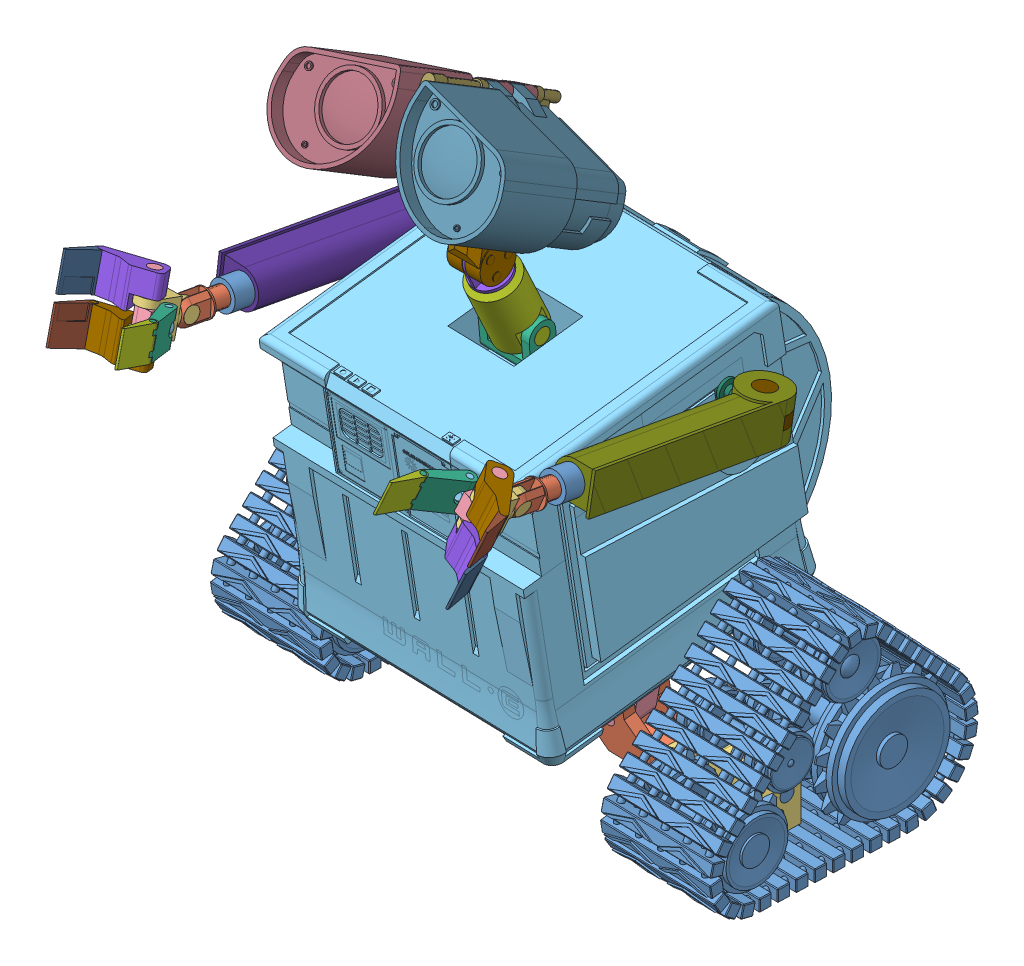
SolidWorks assembly Wall-E 1, configuration Default. Lengths in mm.
Overall size (690.22 894.54 668.06).
46 component instances, 29 part files, 72 mates.
Components (placement in the parent):
- Leg2-1: Leg2 [Default] at (217.59 79.9141 -697.9774) x (0.99964 0 0.026846) z (-0.026526 -0.154085 0.987701) size (150 276.28 351.13)
- Leg2-2: Leg2 [Default] at (-312.2225 80.7609 -712.0739) x (0.99964 0 0.026846) z (-0.026526 -0.154085 0.987701) size (150 276.28 351.13)
- Leg4-1: Leg4 [Default] at (37.1535 79.1519 -684.1405) x (0.99964 0 0.026846) z (-0.026526 -0.154085 0.987701) size (110 70 60)
- Leg4-2: Leg4 [Default] at (-132.7888 79.9987 -688.5724) x (-0.99964 0 -0.026846) z (0.026526 0.154085 -0.987701) size (110 70 60)
- Leg5-1: Leg5 [Default] at (-132.6985 80.2592 -691.9322) x (-0.99964 0 -0.026846) z (0.026846 0 -0.99964) size (135 55 55.64)
- Leg5-2: Leg5 [Default] at (37.2437 79.4124 -687.5004) x (0.99964 0 0.026846) z (-0.026846 0 0.99964) size (135 55 55.64)
- Leg1-1: Leg1 [Default] at (-132.7888 79.9987 -688.5724) x (-0.333574 0.932781 0.136559) z (-0.026526 -0.154085 0.987701) size (150 40 60)
- Leg1-2: Leg1 [Default] at (70.4316 182.6045 -667.1078) x (-0.302528 -0.940479 -0.154843) z (-0.026526 -0.154085 0.987701) size (150 40 60)
- Body2-1: Body2 [Default] at (-49.4424 162.8434 -673.41) x (0.99964 0 0.026846) z (-0.026526 -0.154085 0.987701) size (356.05 350.01 438.03)
- Face 1-1: Face 1 [Default] at (-50.7537 476.0577 -624.5826) x (0.99964 0 0.026846) z (-0.026732 -0.092214 0.99538) size (100 57 34)
- Face2-1: Face2 [Default] at (-50.681 490.0498 -627.2924) x (0.99964 0 0.026846) z (-0.024388 -0.418008 0.908116) size (70 90 60)
- Face3-1: Face3 [Default] at (-51.7528 576.8213 -587.38) x (0.999934 0.011214 0.002475) z (0.002437 -0.417857 0.908509) size (48 63.5 48)
- Face4-1: Face4 [Default] at (-52.0276 599.063 -577.1495) x (0.999934 0.011214 0.002475) z (-0.000596 -0.164604 0.98636) size (46 104.21 107.04)
- Face5-1: Face5 [Default] at (-52.7079 657.9316 -569.0132) x (0.999934 0.011214 0.002475) z (-0.000596 -0.164604 0.98636) size (26 40 80)
- Face6-1: Face6 [Default] at (-53.0415 702.5989 -636.5827) x (0.999934 0.011214 0.002475) z (-0.007905 0.515762 0.856695) size (26 40 16)
- Face7-1: Face7 [Default] at (-54.1993 778.8879 -593.2256) x (0.999773 0.021032 -0.003437) z (-0.007905 0.515762 0.856695) size (16 32 195)
- Eye2-1: Eye2 [Default] at (-69.0806 748.885 -657.0094) x (0.964773 0.229228 -0.129102) z (-0.007905 0.515762 0.856695) size (300 112 205)
- Eye1-1: Eye1 [Default] at (-38.4971 749.5099 -657.1034) x (0.974106 -0.189615 0.123143) z (-0.007905 0.515762 0.856695) size (171 112 205)
- Hand1-1: Hand1 [Default] at (-207.8303 456.7753 -735.5854) x (-0.99964 0 -0.026846) z (0.026526 0.154085 -0.987701) size (28 26 26)
- Hand1-2: Hand1 [Default] at (112.0543 456.7753 -726.9947) x (0.99964 0 0.026846) z (-0.026526 -0.154085 0.987701) size (28 26 26)
- Hand3-1: Hand3 [Default] at (170.0334 456.7753 -725.4376) x (0.999906 -0.002222 0.013542) z (-0.012991 0.164692 0.986259) size (60 52 284)
- Hand3(1)-1: Hand3(1) [Default] at (-425.4358 455.9213 -748.0377) x (0.997665 0.005338 0.068095) z (-0.068217 0.1281 0.989412) size (220 52 284)
- Hand2-1: Hand2 [Default] at (-229.8224 456.7753 -736.176) x (-0.99964 0 -0.026846) z (0.026625 -0.128211 -0.991389) size (66 52 60)
- Hand2-2: Hand2 [Default] at (134.0464 456.7753 -726.404) x (0.99964 0 0.026846) z (-0.026479 0.164707 0.985987) size (66 52 60)
- Hand4-1: Hand4 [Default] at (-268.1118 464.8563 -674.6733) x (0.936168 0.351034 0.019098) z (-0.068217 0.1281 0.989412) size (38 38 212)
- Hand4-2: Hand4 [Default] at (167.2152 467.1554 -663.3303) x (0.999913 -0.000092 0.013187) z (-0.012991 0.164692 0.986259) size (38 38 212)
- Hand5-1: Hand5 [Default] at (-271.8637 471.9018 -620.2556) x (-0.994724 -0.084902 -0.057591) z (-0.068217 0.1281 0.989412) size (34 34 222)
- Hand5-2: Hand5 [Default] at (166.5006 476.2135 -609.086) x (-0.952116 0.299277 -0.062517) z (-0.012991 0.164692 0.986259) size (34 34 222)
- Hand6-1: Hand6 [Default] at (-285.6251 498.3152 -416.4198) x (0.994724 0.084902 0.057591) z (0.080154 -0.292778 -0.952815) size (30 45 77)
- Hand6-2: Hand6 [Default] at (163.5456 510.2277 -405.9349) x (-0.952116 0.299277 -0.062517) z (-0.007303 -0.226682 -0.973942) size (30 45 77)
- Hand7-1: Hand7 [Default] at (-289.4725 512.3686 -370.6847) x (-0.064035 0.952404 -0.298038) z (0.080154 -0.292778 -0.952815) size (100 30 24)
- Hand7-2: Hand7 [Default] at (163.8961 521.1084 -359.1857) x (-0.305649 -0.926849 0.218013) z (-0.007303 -0.226682 -0.973942) size (100 30 24)
- Hand8-1: Hand8 [Default] at (-276.5411 513.4723 -369.936) x (-0.080154 0.292778 0.952815) z (-0.064035 0.952404 -0.298038) size (14 21 42)
- Hand8-2: Hand8 [Default] at (151.5186 524.999 -359.9984) x (-0.007303 -0.226682 -0.973942) z (0.305649 0.926849 -0.218013) size (14 21 42)
- Hand9-1: Hand9 [Default] at (-262.3112 514.6868 -369.1122) x (-0.064035 0.952404 -0.298038) z (-0.430732 -0.295777 -0.852635) size (42 16 63)
- Hand9-2: Hand9 [Default] at (137.8982 529.2803 -360.8928) x (-0.305649 -0.926849 0.218013) z (0.359383 -0.324335 -0.875015) size (42 16 63)
- Hand10-1: Hand10 [Default] at (-240.7746 529.4757 -326.4804) x (-0.064035 0.952404 -0.298038) z (-0.033354 -0.300527 -0.95319) size (42 10 48.5)
- Hand10-2: Hand10 [Default] at (119.9291 545.4971 -317.142) x (-0.305649 -0.926849 0.218013) z (0.031108 -0.238569 -0.970627) size (42 10 48.5)
- Finger1-1: Finger1 [Default] at (157.019 500.2543 -354.2804) x (-0.305649 -0.926849 0.218013) z (0.648657 -0.035078 0.760272) size (45.5 28 75)
- Finger1-2: Finger1 [Default] at (-290.9133 533.7976 -377.3906) x (-0.064035 0.952404 -0.298038) z (-0.924558 0.055793 0.376935) size (45.5 28 75)
- Finger2-1: Finger2 [Default] at (-291.8738 548.0837 -381.8611) x (-0.064035 0.952404 -0.298038) z (-0.924558 0.055793 0.376935) size (115 28 75)
- Finger2-2: Finger2 [Default] at (152.4342 486.3516 -351.0102) x (-0.305649 -0.926849 0.218013) z (0.648657 -0.035078 0.760272) size (115 28 75)
- Finger3-1: Finger3 [Default] at (-346.0692 534.2248 -364.175) x (-0.064035 0.952404 -0.298038) z (-0.345331 0.259053 0.902019) size (45.5 10 46.5)
- Finger3-2: Finger3 [Default] at (199.6168 494.9258 -317.2125) x (-0.305649 -0.926849 0.218013) z (0.360206 0.099395 0.927563) size (45.5 10 46.5)
- Finger4-1: Finger4 [Default] at (-339.3455 434.2224 -332.881) x (-0.064035 0.952404 -0.298038) z (-0.345331 0.259053 0.902019) size (96 10 46.5)
- Finger4-2: Finger4 [Default] at (231.71 592.245 -340.1039) x (-0.305649 -0.926849 0.218013) z (0.360206 0.099395 0.927563) size (96 10 46.5)
Mates (geometry in assembly coordinates):
- Coincident1: coincident: plane of assembly through (0 0 0) normal (0 1 0); plane of Leg2-1 through (189.3959 0 -657.5753) normal (0 -1 0); plane of assembly
- Coincident2: coincident: plane of assembly through (0 0 0) normal (0 1 0); plane of Leg2-2 through (-297.7434 0 -751.4782) normal (0 -1 0); plane of assembly
- Coincident3: coincident: plane of assembly; plane of assembly; plane of Leg2-1 through (226.7926 48.8557 -540.907) normal (-0.026526 -0.154085 0.987701); plane of Leg2-2 through (-303.0199 49.7025 -555.0034) normal (-0.026526 -0.154085 0.987701)
- Coincident5: coincident: circle of assembly; circle of assembly; circle of Leg2-1; circle of Leg5-2
- Coincident6: coincident: circle of assembly; circle of assembly; circle of Leg2-2; circle of Leg5-1
- Coincident7: coincident: circle of assembly; circle of assembly; circle of Leg4-2; circle of Leg5-1
- Coincident9: coincident: circle of assembly; circle of assembly; circle of Leg4-1; circle of Leg5-2
- Coincident11: coincident: circle of assembly; circle of assembly; circle of Leg4-1; circle of Leg1-2
- Coincident12: coincident: circle of assembly; circle of assembly; circle of Leg4-2; circle of Leg1-1
- Coincident13: coincident: circle of assembly; circle of assembly; circle of Leg1-1; circle of Body2-1
- Coincident14: coincident: circle of assembly; circle of assembly; circle of Leg1-2; circle of Body2-1
- Parallel1: parallel: line of assembly; line of Leg5-1 through (-343.1061 91.3726 -679.5764) axis (0.026846 0 -0.99964); plane of assembly
- Parallel3: parallel: line of assembly; line of Leg5-2 through (247.6513 90.5258 -699.8562) axis (-0.026846 0 0.99964); plane of assembly
- Coincident19: coincident: circle of assembly; circle of assembly; circle of Body2-1; circle of Face 1-1
- Coincident20: coincident: circle of assembly; circle of assembly; circle of Face 1-1; circle of Face2-1
- Coincident21: coincident: circle of assembly; circle of assembly; circle of Face2-1; circle of Face3-1
- Coincident22: coincident: circle of assembly; circle of assembly; circle of Face3-1; circle of Face4-1
- Coincident26: coincident: plane of assembly; plane of assembly; plane of Face4-1 through (-39.763 672.1585 -610.8363) normal (-0.999934 -0.011214 -0.002475); plane of Face5-1 through (-39.763 672.1585 -610.8363) normal (0.999934 0.011214 0.002475)
- Coincident27: coincident: plane of assembly; plane of assembly; plane of Face4-1 through (-65.7613 671.867 -610.9007) normal (0.999934 0.011214 0.002475); plane of Face5-1 through (-65.7613 671.867 -610.9007) normal (-0.999934 -0.011214 -0.002475)
- Coincident28: coincident: line of assembly; line of assembly; line of Face4-1 through (-39.763 672.1585 -610.8363) axis (-0.999934 -0.011214 -0.002475); line of Face5-1 through (-39.763 672.1585 -610.8363) axis (-0.999934 -0.011214 -0.002475)
- Coincident30: coincident: line of assembly; line of assembly; line of Face4-1 through (-65.7524 674.336 -625.6961) axis (0.999934 0.011214 0.002475); line of Face5-1 through (-65.7524 674.336 -625.6961) axis (0.999934 0.011214 0.002475)
- Coincident31: coincident: circle of assembly; circle of assembly; circle of Face5-1; circle of Face6-1
- Coincident32: coincident: circle of assembly; circle of assembly; circle of Face6-1; circle of Face7-1
- Coincident33: coincident: circle of assembly; circle of assembly; circle of Face7-1; circle of Eye2-1
- Coincident34: coincident: circle of assembly; circle of assembly; circle of Face7-1; circle of Eye1-1
- Coincident35: coincident: circle of assembly; circle of assembly; circle of Hand1-2; circle of Hand2-2
- Coincident36: coincident: circle of assembly; circle of assembly; circle of Hand3-1; circle of Hand2-2
- Concentric1: concentric: cylinder of assembly; cylinder of assembly; cylinder of Hand3-1 through (164.9157 496.3059 -488.7624) axis (-0.012991 0.164692 0.986259) radius 18; cylinder of Hand4-2 through (164.461 502.0701 -454.2433) axis (0.012991 -0.164692 -0.986259) radius 18
- Concentric2: concentric: cylinder of assembly; cylinder of assembly; cylinder of Hand4-2 through (164.5909 500.4232 -464.1059) axis (-0.012991 0.164692 0.986259) radius 12; cylinder of Hand5-2 through (164.1622 505.8581 -431.5594) axis (0.012991 -0.164692 -0.986259) radius 12
- Coincident37: coincident: circle of assembly; circle of assembly; circle of Hand5-2; circle of Hand6-2
- Coincident38: coincident: circle of assembly; circle of assembly; circle of Hand6-2; circle of Hand7-2
- Coincident39: coincident: circle of assembly; circle of assembly; circle of Hand7-2; circle of Hand8-2
- Coincident40: coincident: circle of assembly; circle of assembly; circle of Hand8-2; circle of Hand9-2
- Coincident41: coincident: circle of assembly; circle of assembly; circle of Hand9-2; circle of Hand10-2
- Coincident43: coincident: circle of assembly; circle of assembly; circle of Hand7-2; circle of Finger1-1
- Coincident44: coincident: circle of assembly; circle of assembly; circle of Hand7-2; circle of Finger2-2
- Coincident45: coincident: circle of assembly; circle of assembly; circle of Finger1-1; circle of Finger3-2
- Coincident46: coincident: circle of assembly; circle of assembly; circle of Finger2-2; circle of Finger4-2
- Coincident47: coincident: plane of assembly; plane of assembly; plane of Body2-1 through (116.3442 448.8526 -737.7337) normal (0.99964 0 0.026846); plane of Hand1-2 through (115.8402 445.925 -718.9674) normal (-0.99964 0 -0.026846)
- Coincident49: coincident: line of assembly; line of assembly; line of Body2-1 through (116.2656 467.6257 -734.8072) axis (0.99964 0 0.026846); line of Hand1-2 through (122.2634 467.6257 -734.6461) axis (-0.99964 0 -0.026846)
- Concentric3: concentric: cylinder of assembly; cylinder of assembly; cylinder of Hand4-1 through (-281.8917 490.7325 -474.812) axis (-0.068217 0.1281 0.989412) radius 12; cylinder of Hand5-1 through (-284.1428 494.9598 -442.1614) axis (0.068217 -0.1281 -0.989412) radius 12
- Concentric4: concentric: cylinder of assembly; cylinder of assembly; cylinder of Hand3(1)-1 through (-280.1862 487.53 -499.5473) axis (-0.068217 0.1281 0.989412) radius 18; cylinder of Hand4-1 through (-282.5738 492.0135 -464.9179) axis (0.068217 -0.1281 -0.989412) radius 18
- Coincident55: coincident: circle of assembly; circle of assembly; circle of Hand6-1; circle of Hand7-1
- Coincident56: coincident: circle of assembly; circle of assembly; circle of Hand5-1; circle of Hand6-1
- Coincident57: coincident: circle of assembly; circle of assembly; circle of Hand7-1; circle of Hand8-1
- Coincident58: coincident: circle of assembly; circle of assembly; circle of Finger1-2; circle of Finger3-1
- Coincident59: coincident: circle of assembly; circle of assembly; circle of Finger2-1; circle of Finger4-1
- Coincident60: coincident: circle of assembly; circle of assembly; circle of Hand9-1; circle of Hand10-1
- Coincident61: coincident: circle of assembly; circle of assembly; circle of Hand8-1; circle of Hand9-1
- Coincident62: coincident: circle of assembly; circle of assembly; circle of Hand7-1; circle of Finger2-1
- Coincident63: coincident: circle of assembly; circle of assembly; circle of Hand7-1; circle of Finger1-2
- Coincident64: coincident: line of assembly; line of assembly; line of Body2-1 through (-211.6162 467.6257 -743.6127) axis (-0.99964 0 -0.026846); line of Hand1-1 through (-217.614 467.6257 -743.7738) axis (0.99964 0 0.026846)
- Coincident65: coincident: plane of assembly; plane of assembly; plane of Body2-1 through (-211.5376 448.8526 -746.5392) normal (-0.99964 0 -0.026846); plane of Hand1-1 through (-211.5376 448.8526 -746.5392) normal (0.99964 0 0.026846)
- Coincident66: coincident: plane of assembly; plane of assembly; plane of Body2-1 through (-211.5376 448.8526 -746.5392) normal (-0.004137 0.988058 0.15403); plane of Hand1-1 through (-217.5355 448.8526 -746.7003) normal (0.004137 -0.988058 -0.15403)
- Coincident67: coincident: plane of assembly; plane of assembly; plane of Body2-1 through (116.3442 448.8526 -737.7337) normal (-0.004137 0.988058 0.15403); plane of Hand1-2 through (121.838 445.925 -718.8063) normal (0.004137 -0.988058 -0.15403)
- Distance1: distance = 25 mm: plane of assembly; plane of assembly; plane of Hand3(1)-1 through (-285.561 430.2595 -482.396) normal (-0.068217 0.1281 0.989412); plane of Hand4-1 through (-268.1095 453.1103 -458.8838) normal (-0.068217 0.1281 0.989412)
- Distance2: distance = 25 mm: plane of assembly; plane of assembly; plane of Hand4-1 through (-268.1095 453.1103 -458.8838) normal (-0.068217 0.1281 0.989412); plane of Hand5-1 through (-284.2793 495.216 -440.1826) normal (-0.068217 0.1281 0.989412)
- Distance3: distance = 25 mm: plane of assembly; plane of assembly; plane of Hand4-2 through (164.3661 460.7014 -447.3365) normal (-0.012991 0.164692 0.986259); plane of Hand3-1 through (169.0244 439.7343 -469.1222) normal (-0.012991 0.164692 0.986259)
- Distance4: distance = 25 mm: plane of assembly; plane of assembly; plane of Hand4-2 through (164.3661 460.7014 -447.3365) normal (-0.012991 0.164692 0.986259); plane of Hand5-2 through (164.1362 506.1875 -429.5868) normal (-0.012991 0.164692 0.986259)
- Distance5: distance = 380 mm: plane of assembly; plane of assembly; plane of Leg2-2 through (-241.0408 66.8345 -568.8904) normal (0.99964 0 0.026846); plane of Leg2-1 through (138.8258 65.9877 -558.8209) normal (-0.99964 0 -0.026846)
- Parallel4: parallel: line of assembly; line of Body2-1 through (-140.0706 476.1055 -464.9815) axis (0.99964 0 0.026846); plane of assembly
- Parallel5: parallel: line of assembly; line of assembly; line of Leg4-1 through (61.2453 99.2308 -649.9876) axis (-0.99964 0 -0.026846); line of Leg4-2 through (-158.6789 100.0775 -655.7617) axis (0.99964 0 0.026846)
- Parallel6: parallel: plane of assembly; plane of assembly; plane of Hand7-2 through (160.1631 512.243 -344.7733) normal (0.007303 0.226682 0.973942); plane of Hand8-2 through (139.1922 530.4764 -353.9936) normal (0.007303 0.226682 0.973942)
- Parallel7: parallel: plane of assembly; plane of assembly; plane of Hand6-2 through (156.36 542.3714 -382.5597) normal (-0.952116 0.299277 -0.062517); plane of Hand7-2 through (142.8497 512.1896 -369.2732) normal (-0.952116 0.299277 -0.062517)
- Parallel9: parallel: plane of assembly; plane of assembly; plane of Hand7-1 through (-291.2348 527.7869 -362.9764) normal (-0.080154 0.292778 0.952815); plane of Hand8-1 through (-264.1708 516.6255 -362.5176) normal (-0.080154 0.292778 0.952815)
- Parallel10: parallel: plane of assembly; plane of assembly; plane of Hand6-1 through (-271.6681 486.943 -380.2657) normal (0.994724 0.084902 0.057591); plane of Hand7-1 through (-271.4061 522.2885 -384.8073) normal (0.994724 0.084902 0.057591)
- Coincident79: coincident: plane of assembly; plane of assembly; plane of Finger3-1 through (-347.7138 554.6092 -390.952) normal (-0.962919 -0.137399 -0.232182); plane of Finger4-1 through (-341.3103 459.3688 -361.1482) normal (-0.962919 -0.137399 -0.232182)
- Coincident84: coincident: plane of assembly; plane of assembly; plane of Finger3-2 through (190.459 465.2188 -330.2071) normal (0.909517 -0.351953 -0.221151); plane of Finger4-2 through (221.0239 557.9037 -352.0084) normal (0.909517 -0.351953 -0.221151)
- Coincident85: coincident: plane of assembly; plane of assembly; plane of Finger3-1 through (-347.7138 554.6092 -390.952) normal (-0.962919 -0.137399 -0.232182); plane of Finger4-1 through (-341.3103 459.3688 -361.1482) normal (-0.962919 -0.137399 -0.232182)
- Coincident86: coincident: plane of assembly; plane of assembly; plane of Finger3-2 through (190.459 465.2188 -330.2071) normal (0.909517 -0.351953 -0.221151); plane of Finger4-2 through (221.0239 557.9037 -352.0084) normal (0.909517 -0.351953 -0.221151)
- Coincident87: coincident: circle of assembly; circle of assembly; circle of Hand3(1)-1; circle of Hand2-1
- Coincident88: coincident: circle of Hand1-1; circle of Hand2-1
